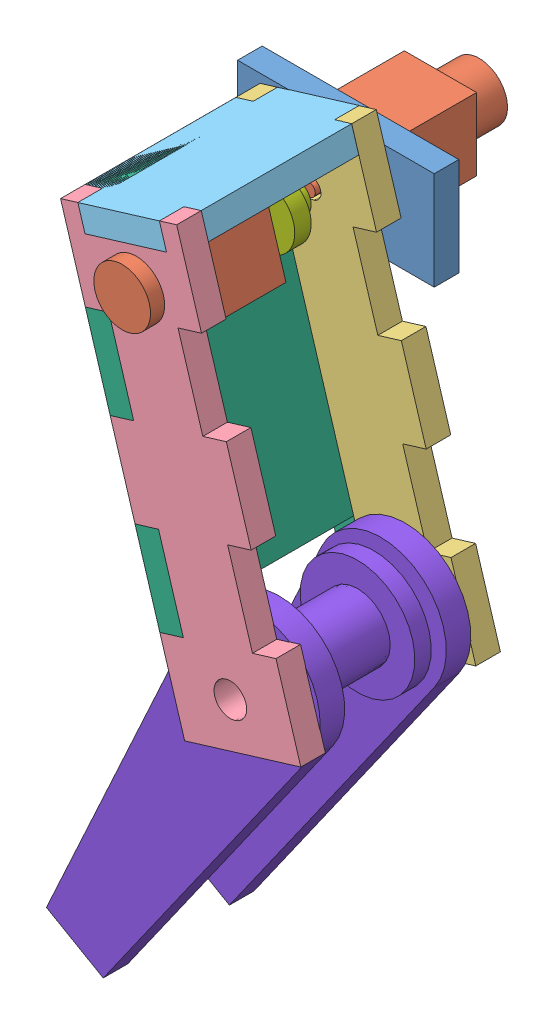
SolidWorks assembly leg_asmb_mk1, configuration Default. Lengths in mm.
Overall size (126.36 282.75 138.35).
10 component instances, 8 part files, 25 mates.
Components (placement in the parent):
- Mock_body_mk1-1: Mock_body_mk1 [Default] at origin size (76.2 38.1 9.53)
- mock_stepper_motor_mk1-1: mock_stepper_motor_mk1 [Default] at (52.1 -5.05 0) x (-1 0 0) z (0 0 -1) size (28 28 66)
- Thigh_inside_mk1-1: Thigh_inside_mk1 [Default] at (8.7411 -3.4004 9.525) x (0.956608 0.291377 0) z (0 0 1) size (47.05 165.1 9.53)
- Thigh_outside_mk1-1: Thigh_outside_mk1 [Default] at (8.7411 -3.4004 77.35) x (0.956608 0.291377 0) z (0 0 1) size (47.05 165.1 9.53)
- mock_stepper_motor_mk1-2: mock_stepper_motor_mk1 [Default] at (20.6282 -9.7368 46.35) x (0.956608 0.291377 0) z (0 0 1) size (28 28 66)
- Thigh_top_mk1-1: Thigh_top_mk1 [Default] at (56.4962 1.1884 9.405) x (0 0 1) z (-0.956608 -0.291377 0) size (77.47 9.53 46.99)
- Thigh_front_back_mk1-1: Thigh_front_back_mk1 [Default] at (44.6379 7.5335 86.875) x (0.956608 0.291377 0) z (0 0 1) size (9.53 132.08 77.47) (hidden)
- Thigh_front_back_mk1-2: Thigh_front_back_mk1 [Default] at (8.7411 -3.4004 86.875) x (0.956608 0.291377 0) z (0 0 1) size (9.53 132.08 77.47)
- mock_pulley_mk1-1: mock_pulley_mk1 [Default] at (38.1 -19.05 31.1125) size (24 24 12.7)
- Calf_half_mk1-2: Calf_half_mk1 [Default] at (74.5411 -138.6882 77.47) x (-0.866798 0.49866 0) z (0 0 -1) size (50.8 165.1 58.42)
Mates (geometry in assembly coordinates):
- Coincident1: coincident aligned: plane of Mock_body_mk1-1 through (0 0 0) normal (0 0 1)
- Coincident2: coincident aligned: plane of Mock_body_mk1-1 through (0 0 0) normal (0 1 0)
- Coincident3: coincident aligned: plane of Mock_body_mk1-1 through (0 0 0) normal (1 0 0)
- Concentric1: concentric aligned: cylinder of Mock_body_mk1-1 through (38.1 -19.05 9.525) axis (0 0 -1) radius 3.75; cylinder of mock_stepper_motor_mk1-1 through (38.1 -19.05 20) axis (0 0 -1) radius 2.5
- Coincident4: coincident anti-aligned: plane of Mock_body_mk1-1 through (0 0 0) normal (0 0 -1); plane of mock_stepper_motor_mk1-1 through (52.1 -5.05 0) normal (0 0 1)
- Coincident5: coincident anti-aligned: plane of Thigh_outside_mk1-1 through (8.7411 -3.4004 77.35) normal (0 0 -1); plane of mock_stepper_motor_mk1-2 through (20.6282 -9.7368 77.35) normal (0 0 1)
- Parallel1: parallel aligned: plane of Thigh_outside_mk1-1 through (11.5165 -12.5121 86.875) normal (-0.291377 0.956608 0); plane of mock_stepper_motor_mk1-2 through (20.6282 -9.7368 92.35) normal (-0.291377 0.956608 0)
- Coincident7: coincident anti-aligned: plane of Mock_body_mk1-1 through (0 0 9.525) normal (0 0 1); plane of Thigh_inside_mk1-1 through (8.7411 -3.4004 9.525) normal (0 0 -1)
- Concentric2: concentric aligned: cylinder of mock_stepper_motor_mk1-1 through (38.1 -19.05 20) axis (0 0 -1) radius 2.5; cylinder of Thigh_inside_mk1-1 through (38.1 -19.05 19.05) axis (0 0 -1) radius 3.75
- Distance1: distance = 6.35 mm anti-aligned: plane of mock_stepper_motor_mk1-2 through (20.6282 -9.7368 26.35) normal (0 0 -1); plane of mock_stepper_motor_mk1-1 through (52.1 -5.05 20) normal (0 0 1)
- Coincident9: coincident aligned: plane of Thigh_inside_mk1-1 through (53.7496 10.3089 19.05) normal (0.956608 0.291377 0); plane of Thigh_outside_mk1-1 through (53.7496 10.3089 86.875) normal (0.956608 0.291377 0)
- Concentric3: concentric anti-aligned: cylinder of Thigh_outside_mk1-1 through (38.1 -19.05 86.875) axis (0 0 -1) radius 11; cylinder of mock_stepper_motor_mk1-2 through (38.1 -19.05 77.35) axis (0 0 1) radius 11
- Coincident10: coincident aligned: plane of Thigh_inside_mk1-1 through (11.5165 -12.5121 19.05) normal (-0.291377 0.956608 0); plane of Thigh_outside_mk1-1 through (11.5165 -12.5121 86.875) normal (-0.291377 0.956608 0)
- Coincident11: coincident anti-aligned: plane of Thigh_outside_mk1-1 through (15.4518 -1.3564 86.875) normal (0.956608 0.291377 0); plane of Thigh_top_mk1-1 through (15.4518 -1.3564 9.405) normal (-0.956608 -0.291377 0)
- Coincident12: coincident anti-aligned: plane of Thigh_outside_mk1-1 through (8.7411 -3.4004 77.35) normal (0 0 -1); plane of Thigh_top_mk1-1 through (53.7209 10.3001 77.35) normal (0 0 1)
- Coincident13: coincident anti-aligned: plane of Thigh_outside_mk1-1 through (11.5165 -12.5121 86.875) normal (-0.291377 0.956608 0); plane of Thigh_top_mk1-1 through (56.4962 1.1884 9.405) normal (0.291377 -0.956608 0)
- Coincident14: coincident anti-aligned: plane of Thigh_outside_mk1-1 through (18.3624 -34.9876 86.875) normal (0.291377 -0.956608 0); plane of Thigh_front_back_mk1-1 through (63.3708 -21.2783 86.875) normal (-0.291377 0.956608 0)
- Coincident15: coincident anti-aligned: plane of Thigh_outside_mk1-1 through (8.7411 -3.4004 77.35) normal (0 0 -1); plane of Thigh_front_back_mk1-1 through (53.7496 10.3089 77.35) normal (0 0 1)
- Coincident16: coincident aligned: plane of Thigh_outside_mk1-1 through (53.7496 10.3089 86.875) normal (0.956608 0.291377 0); plane of Thigh_front_back_mk1-1 through (53.7496 10.3089 86.875) normal (0.956608 0.291377 0)
- Coincident17: coincident anti-aligned: plane of Thigh_outside_mk1-1 through (18.3624 -34.9876 86.875) normal (0.291377 -0.956608 0); plane of Thigh_front_back_mk1-2 through (27.4741 -32.2123 86.875) normal (-0.291377 0.956608 0)
- Coincident18: coincident aligned: plane of Thigh_outside_mk1-1 through (8.7411 -3.4004 86.875) normal (-0.956608 -0.291377 0); plane of Thigh_front_back_mk1-2 through (8.7411 -3.4004 86.875) normal (-0.956608 -0.291377 0)
- Coincident19: coincident aligned: plane of Thigh_outside_mk1-1 through (8.7411 -3.4004 86.875) normal (0 0 1); plane of Thigh_front_back_mk1-2 through (17.8528 -0.6251 86.875) normal (0 0 1)
- Coincident20: coincident anti-aligned: plane of mock_stepper_motor_mk1-2 through (20.6282 -9.7368 26.35) normal (0 0 -1); plane of mock_pulley_mk1-1 through (38.1 -19.05 26.35) normal (0 0 1)
- Concentric4: concentric anti-aligned: cylinder of mock_stepper_motor_mk1-2 through (38.1 -19.05 26.35) axis (0 0 1) radius 2.5; cylinder of mock_pulley_mk1-1 through (38.1 -19.05 37.4625) axis (0 0 -1) radius 2.5
- Coincident25: coincident anti-aligned: circle of Thigh_inside_mk1-1; circle of Calf_half_mk1-2
